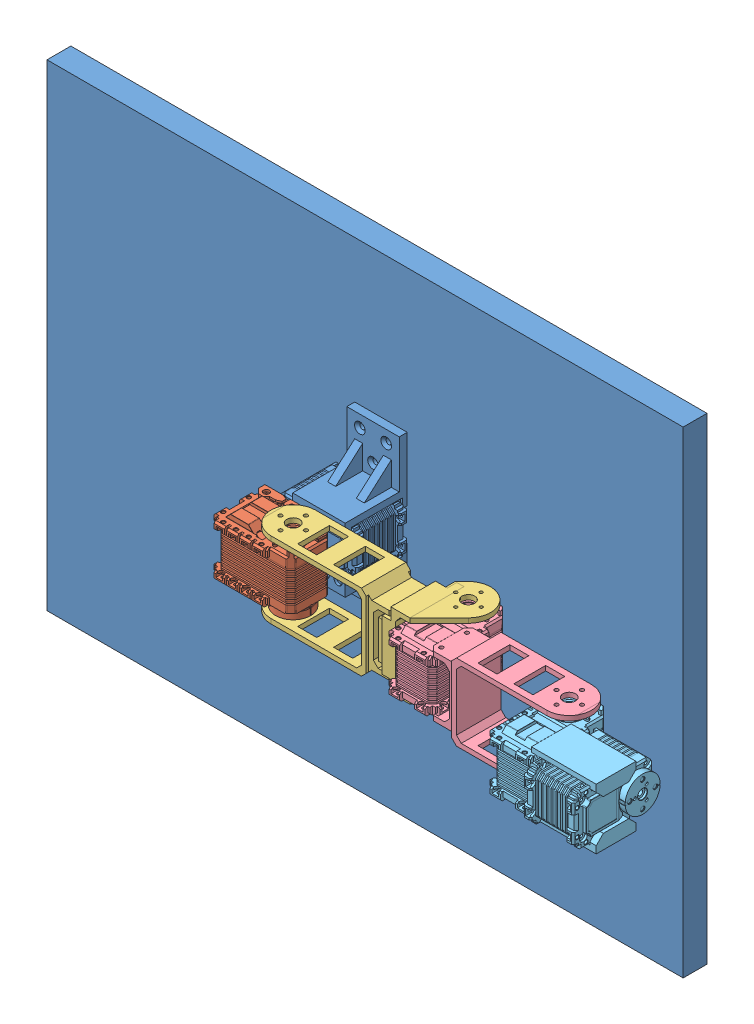
SolidWorks assembly Montagem1, configuration Valor predeterminado. Lengths in mm.
Overall size (447.89 300 126.82).
5 component instances, 5 part files, 9 mates.
Components (placement in the parent):
- 00-1: 00 [Valor predeterminado] at (-25.4062 -17.1844 400) size (400 300 55.05)
- 01-1: 01 [Valor predeterminado] at (-16.2295 -7.5928 815.464) size (50.01 40.06 35)
- 02-1: 02 [Valor predeterminado] at (23.3961 4.5288 776.6) size (124.39 48 42.28)
- 03-1: 03 [Valor predeterminado] at (95.766 -5.7262 816.1937) size (115.9 48 50.01)
- 04-1: 04 [Valor predeterminado] at (182.3793 -6.5024 838.6937) size (67.8 40.06 55.61)
Mates (geometry in assembly coordinates):
- Coincidente1: coincident: plane of 00-1 through (-27.9665 -7.6443 847.5) normal (0 0 1); plane of 01-1 through (-27.9665 -7.6443 847.5) normal (0 0 -1)
- Concêntrico1: concentric: circle of 00-1; circle of 01-1
- Concêntrico2: concentric: circle of 01-1; circle of 02-1
- Coincidente3: coincident: plane of 01-1 through (-5.6665 -28.6443 866.5) normal (0 -1 0); plane of 02-1 through (-17.7665 -28.6443 880.5) normal (0 1 0)
- Concêntrico3: concentric: circle of 02-1; circle of 03-1
- Concêntrico4: concentric: cylinder of 02-1 through (82.7187 -34.1443 852.7157) axis (0 1 0) radius 1; cone of 03-1 through (82.7187 -27.9445 852.7157) axis (0 1 0)
- Coincidente4: coincident: plane of 02-1 through (82.2335 -28.1443 867) normal (0 1 0); plane of 03-1 through (90.7187 -28.1443 852.7157) normal (0 -1 0)
- Coincidente8: coincident: plane of 03-1 through (188.7187 -28.1443 889.2157) normal (0 1 0); plane of 04-1 through (176.6187 -28.1443 875.2157) normal (0 -1 0)
- Concêntrico6: concentric: circle of 03-1; circle of 04-1
